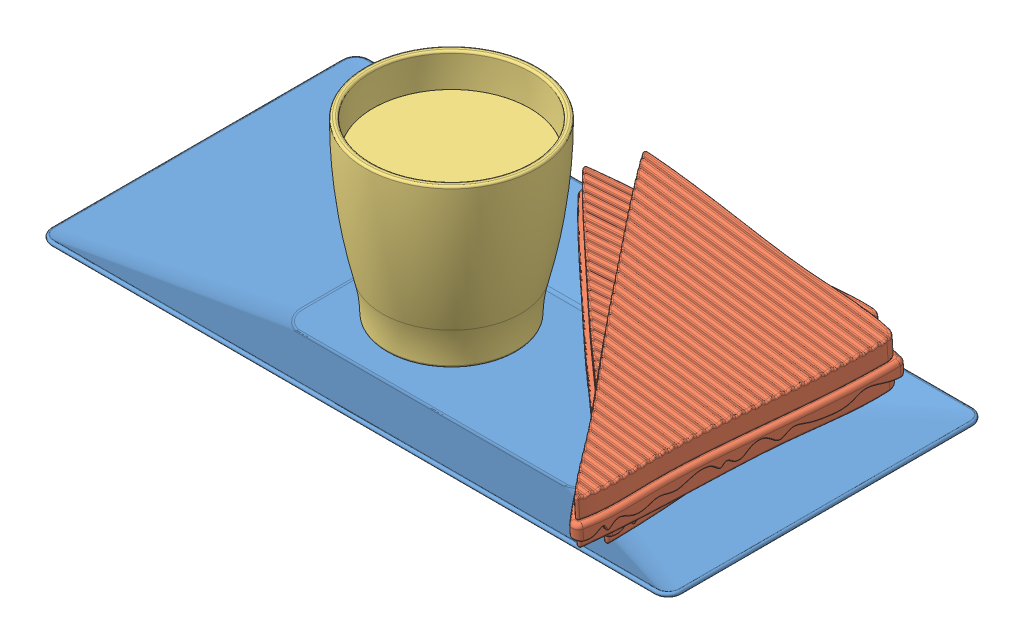
SolidWorks assembly Grilled Cheese Plate, configuration Default. Lengths in mm.
Overall size (357.95 114.18 241.7).
13 component instances, 4 part files, 1 mates.
Components (placement in the parent):
- Plate-1: Plate [Default] at origin size (311.49 59.69 166.82)
- Grilled Cheese-3: Grilled Cheese [Default] at (39.5176 9.2037 1.5378) x (0.730902 0.008805 0.682426) z (-0.68159 -0.041694 0.730545) size (197.58 29.94 114.63)
  - Grilled Cheese-1: Grilled Cheese [Default] at origin size (197.58 29.94 114.63)
  - Grilled Cheese-2: Grilled Cheese [Bottom] at (0 -2 0) x (-1 0 0) z (0 0 1) size (188.07 19.76 99.88)
- Grilled Cheese-4: Grilled Cheese [Default] at (60.0641 28.3213 14.6037) x (0.616376 -0.041265 0.78637) z (-0.787425 -0.040516 0.615077) size (197.58 29.94 114.63)
  - Grilled Cheese-1: Grilled Cheese [Default] at origin size (197.58 29.94 114.63)
  - Grilled Cheese-2: Grilled Cheese [Bottom] at (0 -2 0) x (-1 0 0) z (0 0 1) size (188.07 19.76 99.88)
- Gaspatxo-1: Gaspatxo [Default] at (-32.6346 -15 -4.572) size (80 80 80)
- chip-1: chip [Default] at (-43.9734 -10.8273 46.5916) x (0.480046 -0.704478 0.522749) z (0.311389 0.693936 0.649223) (suppressed, hidden)
- chip-2: chip [Default] at (1.9928 -21.9518 2.6601) x (0.158482 -0.843409 0.513366) z (-0.513859 0.37352 0.77229) (suppressed, hidden)
- chip-3: chip [Default] at (-106.4962 -16.6266 -84.7865) x (0.087931 -0.904687 0.416904) z (-0.789297 0.192041 0.583206) (suppressed, hidden)
- chip-4: chip [Default] at (-118.8662 30.3091 31.4187) x (-0.326912 -0.370459 0.869419) z (0.390045 0.785068 0.481179) (suppressed, hidden)
- chip-5: chip [Default] at (-145.102 2.4578 -14.9418) x (-0.14385 -0.472671 0.869419) z (0.029364 0.876131 0.481179) (suppressed, hidden)
Mates (geometry in assembly coordinates):
- Coincident1: coincident anti-aligned: plane of Plate-1 through (79.134 -15 36.8698) normal (0 1 0); plane of Gaspatxo-1 through (-62.6466 -15 -4.572) normal (0 -1 0)
